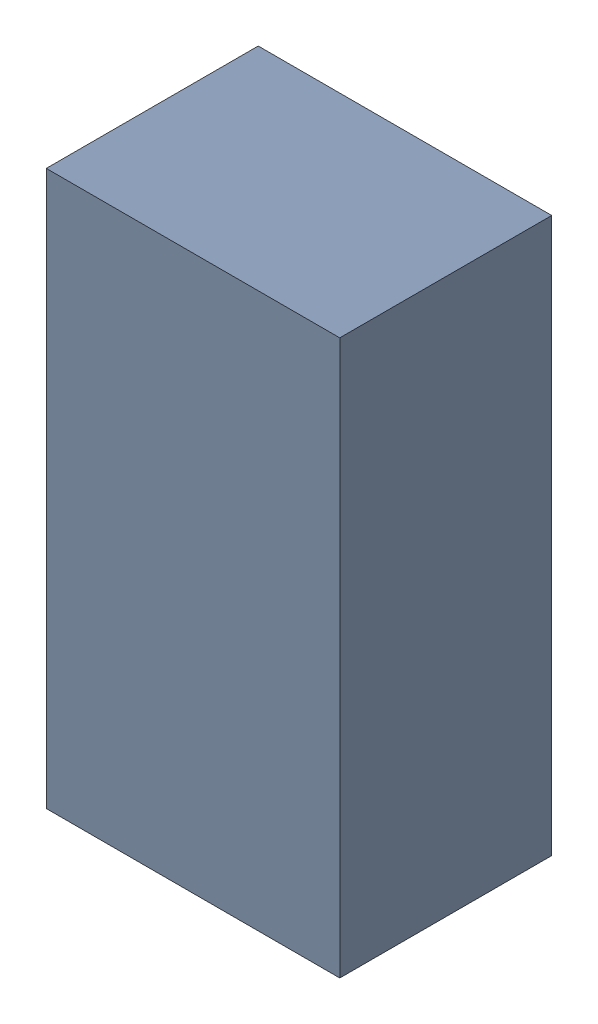
SolidWorks assembly C204, configuration Standard. Lengths in mm.
Overall size (1.8 3.4 1.3).
2 component instances, 1 part files, 0 mates.
Components (placement in the parent):
- 885541968-1: 885541968 [Standard] at (19.32 12.68 0) size (1.8 3.4 1.3)
  - Extruded_30-1: Extruded_30 [Standard] at origin size (1.8 3.4 1.3)
